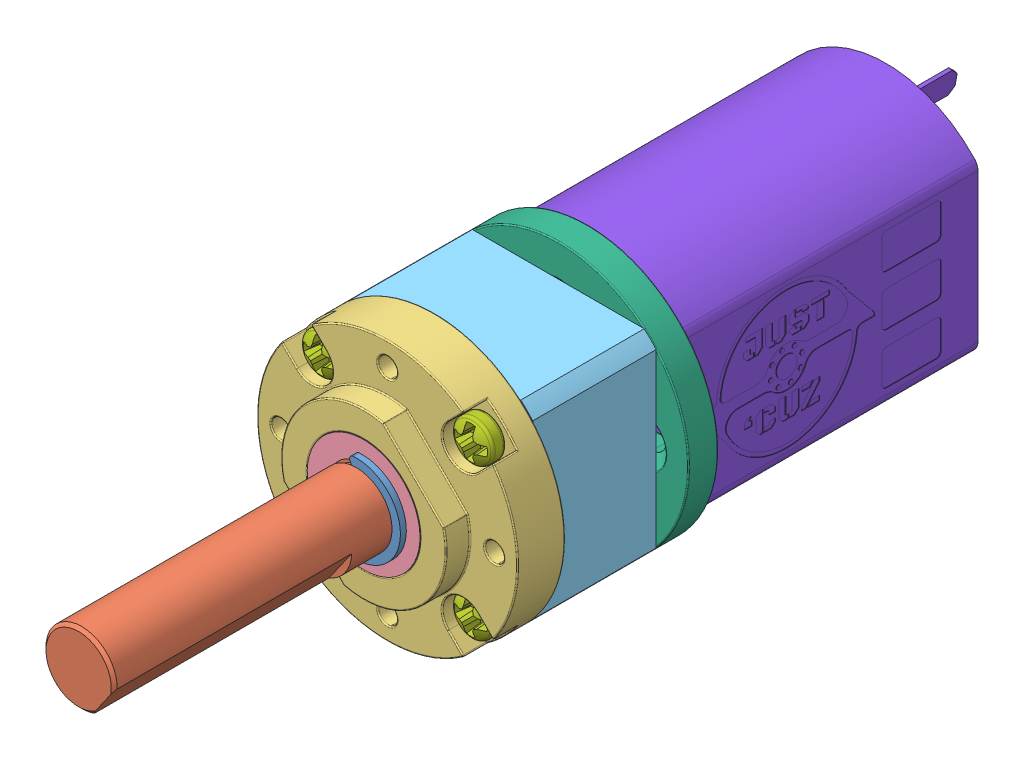
SolidWorks assembly DartBox V2 6mm Shaft.stp, configuration Default. Lengths in mm.
Overall size (21.95 21.95 72.3).
15 component instances, 8 part files, 0 mates.
Components (placement in the parent):
- DartBox V2 Drive 6mm Output.stp-1: DartBox V2 Drive 6mm Output.stp [Default] at (0 15.4164 54.362) x (0 1 0) z (0 0 1) size (21.95 21.95 42.9)
  - Ring Gear.stp-1: Ring Gear.stp [Default] at (-10.101 0.0152 -54.1116) x (0 -1 0) z (0 0 1) size (21.95 21.95 40.4)
    - Front Plate.stp-1: Front Plate.stp [Default] at (0.0152 10.101 56.6116) x (0 1 0) z (1 0 0) size (21.95 30.5 21.95)
      - Shaft.stp-1: Shaft.stp [Default] x (-0.819152 0 -0.573576) z (0.573576 0 -0.819152) size (7.4 30.3 6.7)
        - Retaining Ring.stp-1: Retaining Ring.stp [Default] at (0 16.65 0) x (-1 0 0) z (0 -1 0) size (7.4 6.16 0.5)
        - Shaft-0.stp-1: Shaft-0.stp [Default] at origin size (6 30.3 6)
      - Front Plate-1.stp-1: Front Plate-1.stp [Default] at origin size (21.95 6.5 21.95)
      - Front Plate-2.stp-1: Front Plate-2.stp [Default] at origin size (9.5 6 9.5)
    - Ring Gear Body.stp-1: Ring Gear Body.stp [Default] at (0.0152 10.101 56.6116) x (0 1 0) z (1 0 0) size (16.5 10.4 16.5)
  - Motor Mount Plate.stp-1: Motor Mount Plate.stp [Default] at (0 0 2.5) x (1 0 0) z (0 -1 0) size (21.95 3.5 21.95)
  - Screws M2 x 14mm.stp-1: Screws M2 x 14mm.stp [Default] at (6.364 6.364 0.9) size (3.4 3.4 15.61)
  - Screws M2 x 14mm.stp-2: Screws M2 x 14mm.stp [Default] at (-6.364 6.364 0.9) x (0 1 0) z (0 0 1) size (3.4 3.4 15.61)
  - Screws M2 x 14mm.stp-3: Screws M2 x 14mm.stp [Default] at (-6.364 -6.364 0.9) x (-1 0 0) z (0 0 1) size (3.4 3.4 15.61)
  - Screws M2 x 14mm.stp-4: Screws M2 x 14mm.stp [Default] at (6.364 -6.364 0.9) x (0 -1 0) z (0 0 1) size (3.4 3.4 15.61)
- DartBox 130 motor.stp-1: DartBox 130 motor.stp [Default] at (0 15.4164 54.362) x (1 0 0) z (0 0 -1) size (15.5 20.4 34.9)
